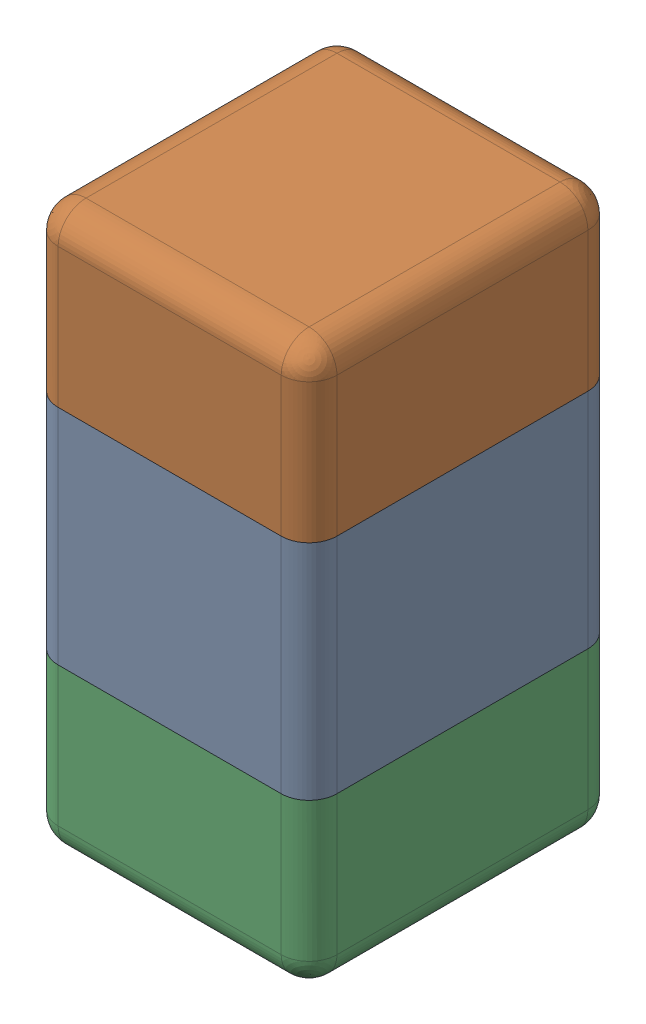
SolidWorks assembly C11, configuration Default. Lengths in mm.
Overall size (0.51 1.01 0.56).
5 component instances, 4 part files, 0 mates.
Components (placement in the parent):
- Cap_Kemet_C0402C562J5RACTU_eec-1: Cap_Kemet_C0402C562J5RACTU_eec [Default] at (149 90 -1.6914) x (0 -1 0) z (0 0 -1) size (1.01 0.51 0.56)
  - body_2-1: body_2 [Default] at origin size (0.4 0.5 0.55)
  - terminals-1: terminals [Default] at origin size (0.31 0.51 0.56)
  - terminals_2-1: terminals_2 [Default] at origin size (0.31 0.51 0.56)
  - value-1: value [Default] at (0 0 0.55) size (0.37 0.29 0.15)
